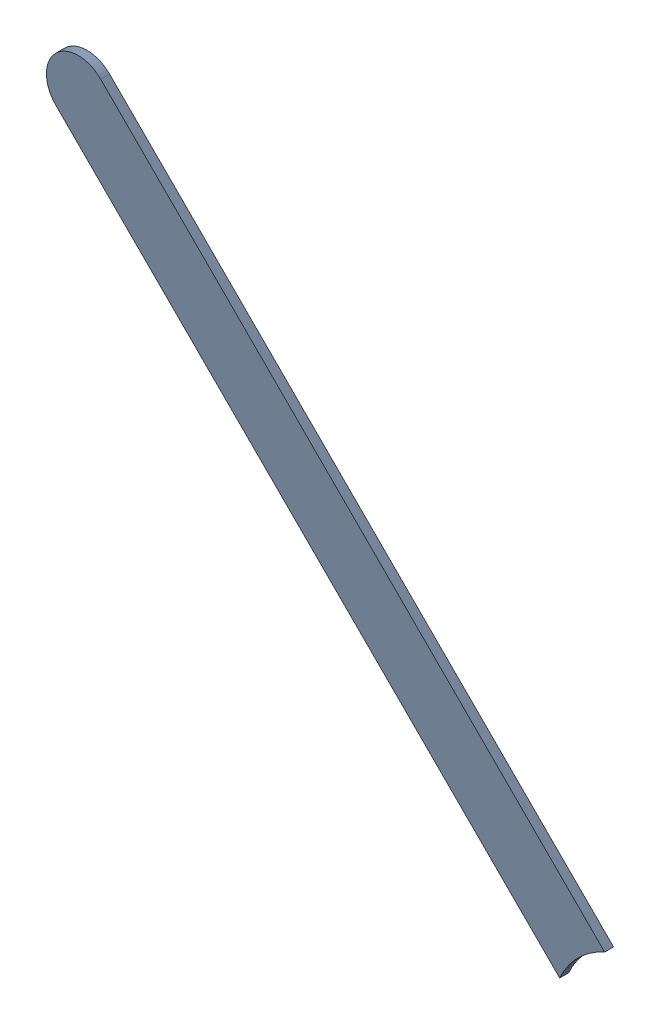
SolidWorks assembly Track (25.5mm,40.8mm)(27.75mm,38.55mm) on Bottom Layer, configuration Predeterminado. Lengths in mm.
Overall size (2.23 2.23 0.04).
2 component instances, 1 part files, 0 mates.
Components (placement in the parent):
- Track (25.5mm,40.8mm)(27.75mm,38.55mm) on Bottom Layer-1-1: Track (25.5mm,40.8mm)(27.75mm,38.55mm) on Bottom Layer-1 [Predeterminado] at (-68.317 -44.187 -0.4013) size (2.23 2.23 0.04)
  - Track (25.5mm,40.8mm)(27.75mm,38.55mm) on Bottom Layer-Part-1-1: Track (25.5mm,40.8mm)(27.75mm,38.55mm) on Bottom Layer-Part-1 [Predeterminado] at origin size (2.23 2.23 0.04)
